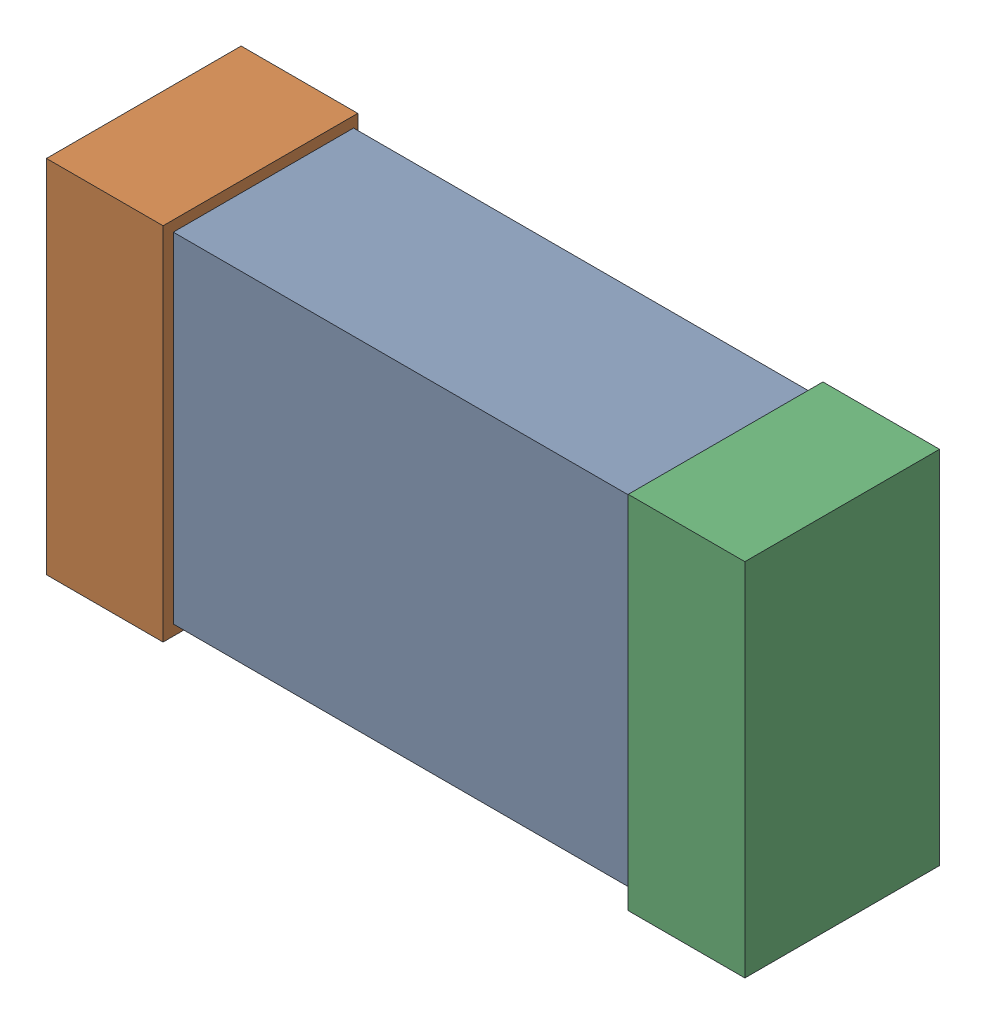
SolidWorks assembly R22, configuration Default. Lengths in mm.
Overall size (1.65 0.85 0.46).
6 component instances, 2 part files, 0 mates.
Components (placement in the parent):
- 432120720_21-1: 432120720_21 [Default] at (33.4343 48.9603 -0.8615) size (1.5 0.8 0.42)
  - Extruded (12)-1: Extruded (12) [Default] at origin size (1.5 0.8 0.42)
- 432120464_44-1: 432120464_44 [Default] at (32.7485 48.9603 -0.8715) size (0.28 0.85 0.46)
  - Extruded (11)-1: Extruded (11) [Default] at origin size (0.28 0.85 0.46)
- 432120464_45-1: 432120464_45 [Default] at (34.12 48.9603 -0.8715) size (0.28 0.85 0.46)
  - Extruded (11)-1: Extruded (11) [Default] at origin size (0.28 0.85 0.46)
